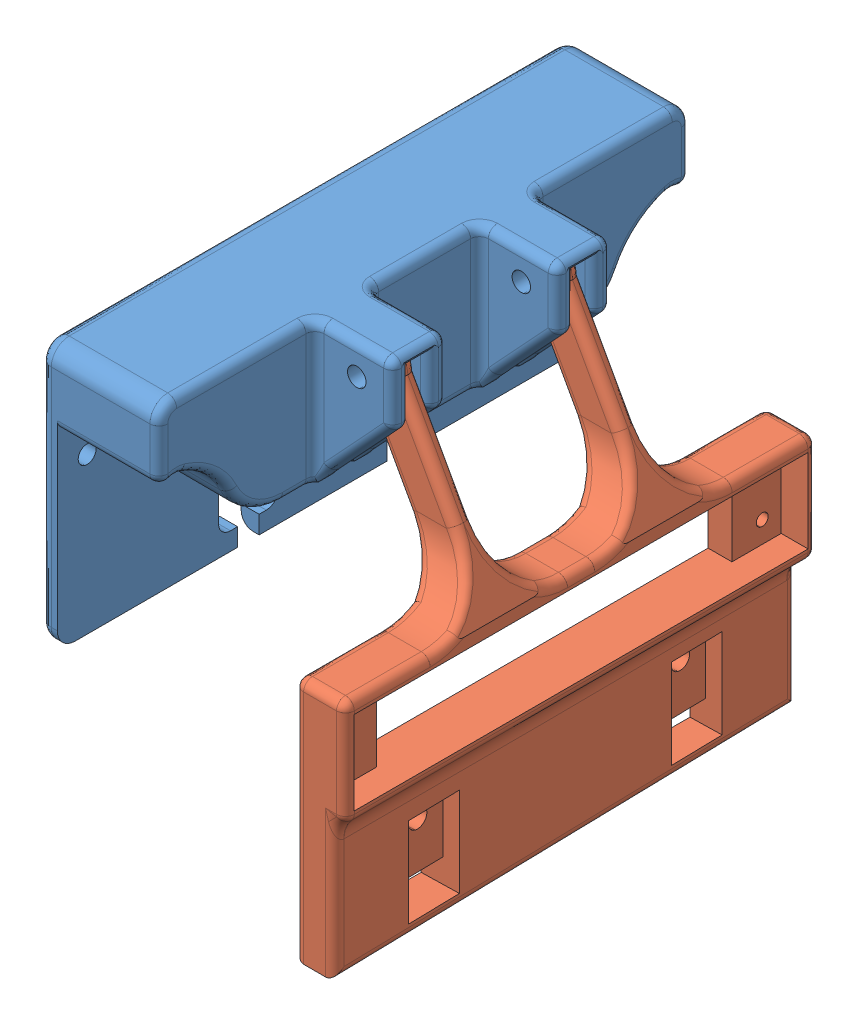
SolidWorks assembly Montagem1, configuration Valor predeterminado. Lengths in mm.
Overall size (46.3 73.5 89).
2 component instances, 2 part files, 3 mates.
Components (placement in the parent):
- SuporteDoArraynovonovo-1: SuporteDoArraynovonovo [Valor predeterminado] at (-12.1143 -5.6038 -16.0984) size (33 43.75 89)
- Peça5-1: Peça5 [Valor predeterminado] at (10.0814 13.29 -12.28) x (0 -1 0) z (0 0 -1) size (72.5 23.3 78.95)
Mates (geometry in assembly coordinates):
- Concêntrico1: concentric aligned: circle of SuporteDoArraynovonovo-1; circle of Peça5-1
- Distância1: distance = 0.05 mm anti-aligned: plane of Peça5-1 through (10.0814 13.29 15.3) normal (0 0 1); plane of SuporteDoArraynovonovo-1 through (17.8857 18.3731 15.35) normal (0 0 -1)
- Paralelo1: parallel anti-aligned: plane of SuporteDoArraynovonovo-1 through (-12.1143 -22.3769 41.5) normal (1 0 0); plane of Peça5-1 through (22.6253 -14.1269 -39.455) normal (-1 0 0)
